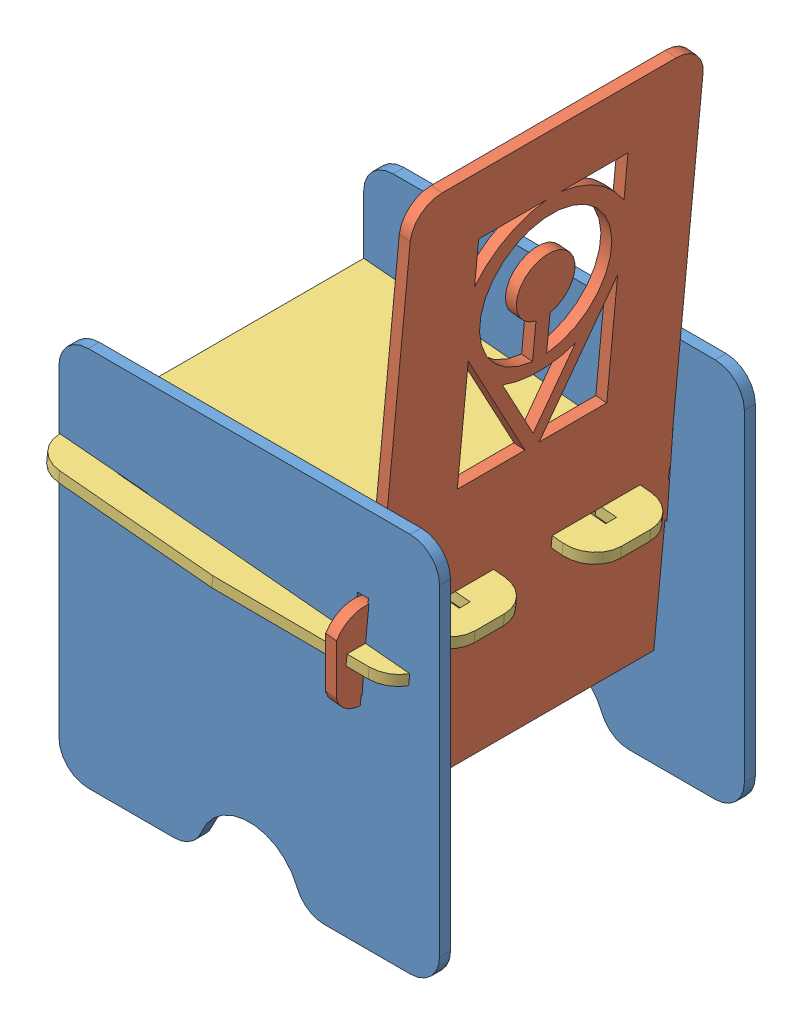
SolidWorks assembly Test case 2, configuration Default. Lengths in mm.
Overall size (13.04 22.31 12.85).
4 component instances, 3 part files, 7 mates.
Components (placement in the parent):
- part 2-1: part 2 [Default] at (-0.2053 -1.7923 10.4422) size (13 13 0.38)
- part 1-1: part 1 [Default] at (9.7366 1.5647 0.4422) x (0 0 1) z (-0.995633 0.093358 0) size (12.85 19 0.38)
- part 2-2: part 2 [Default] at (-0.1703 -1.7954 0.0673) size (13 13 0.38)
- Part3-1: Part3 [Default] at (-0.2053 7.8327 -0.9294) x (0 0 1) z (0.093358 0.995633 0) size (12.75 12 0.38)
Mates (geometry in assembly coordinates):
- Distance6: distance = 10 mm: line of part 2-2 through (-0.1703 -0.7954 0.4423) axis (0 1 0); line of part 2-1 through (-0.2053 -0.7923 10.4422) axis (0 1 0)
- Coincident50: coincident: plane of part 2-1 through (6.2947 -1.7923 10.4422) normal (0 0 -1); line of part 1-1 through (9.3633 1.5997 10.4422) axis (0.093358 0.995633 0)
- Coincident66: coincident anti-aligned: line of part 2-1 through (-0.2053 7.8327 10.8172) axis (0 0 -1); line of Part3-1 through (-0.2053 7.8327 0.0706) axis (0 0 1)
- Angle8: planar angle = 1.570796 rad anti-aligned: plane of part 1-1 through (9.9161 7.4954 10.946) normal (-0.995633 0.093358 0); plane of Part3-1 through (10.8773 7.1702 0.4984) normal (0.093358 0.995633 0)
- Coincident74: coincident: line of part 1-1 through (9.8942 7.2623 4.4422) axis (0 0 -1); plane of Part3-1 through (10.8773 7.1702 0.4984) normal (0.093358 0.995633 0)
- Coincident81: coincident anti-aligned: line of part 2-2 through (-0.1703 8.2061 0.4423) axis (0 0 -1); line of Part3-1 through (-0.1703 8.2061 0.0706) axis (0 0 1)
- Distance17: distance = 0.23 mm: line of part 1-1 through (9.7769 6.0112 11.7006) axis (0.093003 0.991844 0.087156); line of part 2-1 through (9.7721 5.6057 10.8172) axis (0.07244 0.997373 0)
